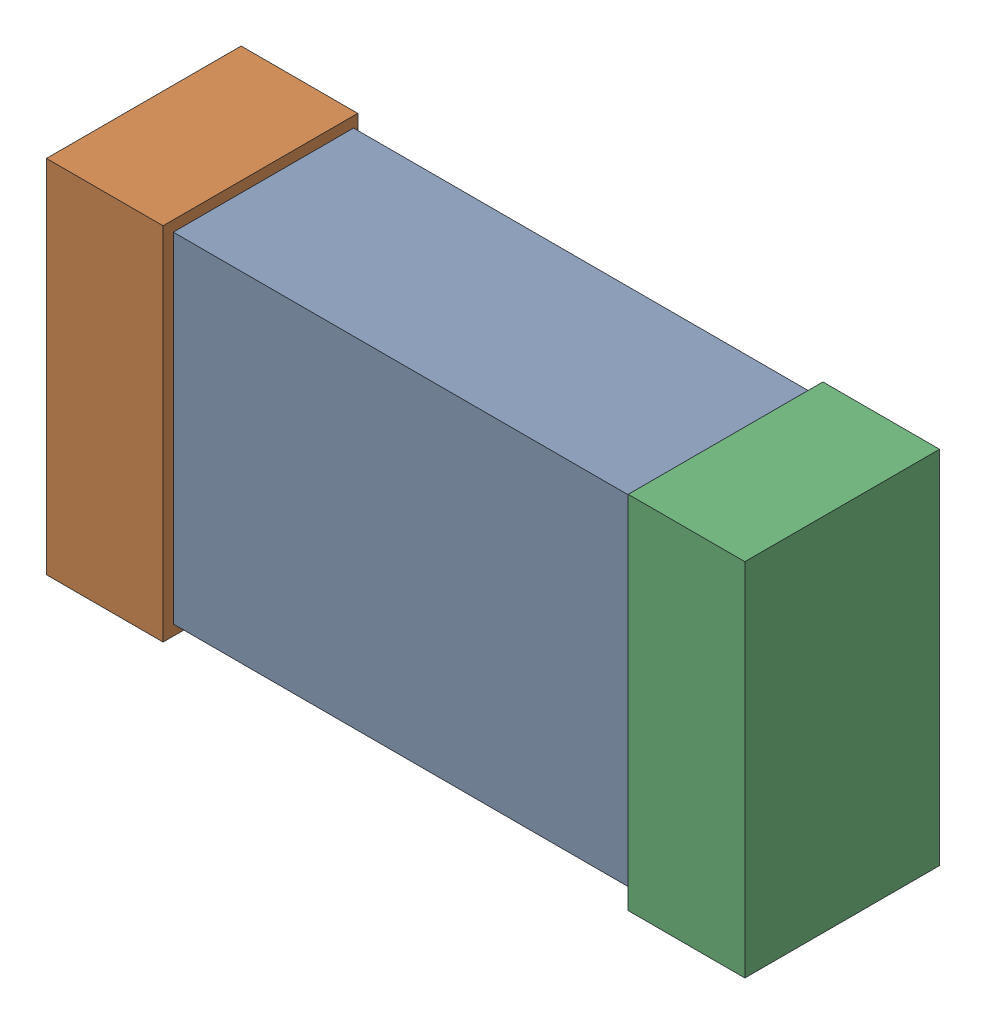
SolidWorks assembly R35, configuration Default. Lengths in mm.
Overall size (1.65 0.85 0.46).
6 component instances, 2 part files, 0 mates.
Components (placement in the parent):
- 432120720_2-1: 432120720_2 [Default] at (7.4501 32.6999 -0.8615) size (1.5 0.8 0.42)
  - Extruded (12)-1: Extruded (12) [Default] at origin size (1.5 0.8 0.42)
- 432120464_4-1: 432120464_4 [Default] at (6.7643 32.6999 -0.8715) size (0.28 0.85 0.46)
  - Extruded (11)-1: Extruded (11) [Default] at origin size (0.28 0.85 0.46)
- 432120464_5-1: 432120464_5 [Default] at (8.1358 32.6999 -0.8715) size (0.28 0.85 0.46)
  - Extruded (11)-1: Extruded (11) [Default] at origin size (0.28 0.85 0.46)
